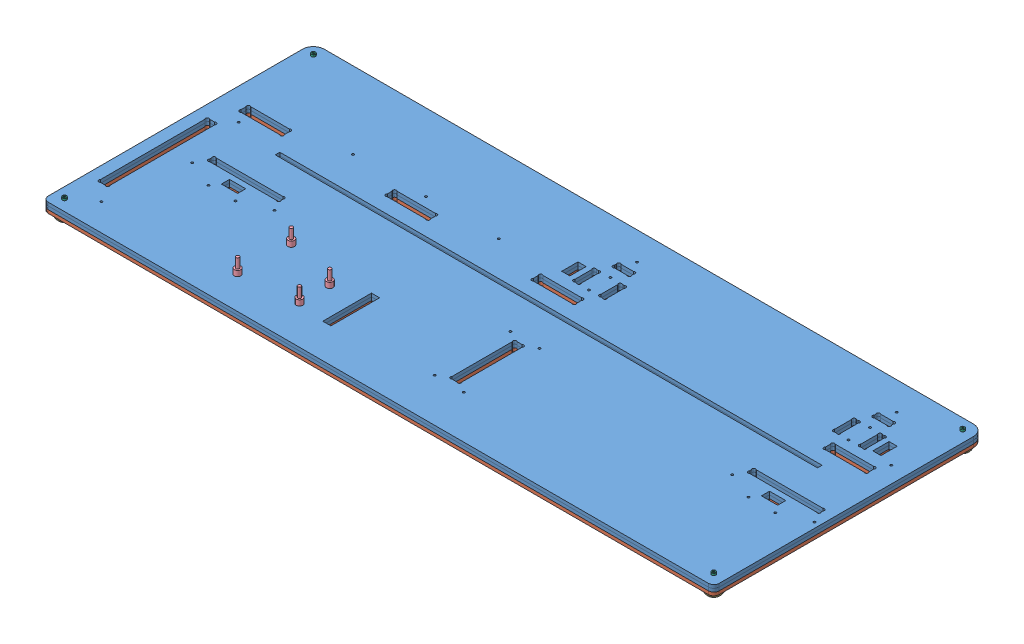
SolidWorks assembly socle-complet, configuration Défaut. Lengths in mm.
Overall size (621.62 30.74 251.62).
21 component instances, 6 part files, 49 mates.
Components (placement in the parent):
- socle-1-1: socle-1 [Défaut] at (-302.5453 40.1785 745) size (620 3 250)
- socle-1-2: socle-1 [Défaut] at (-302.5453 37.1785 745) size (620 3 250)
- socle-2-3: socle-2 [Défaut] at (-302.5453 34.1785 745) size (620 3 250)
- socle-patin-ecrou_m2-1: socle-patin-ecrou_m2 [Défaut] at (-292.5453 34.1785 735) x (0.367083 0 0.930188) z (-0.930188 0 0.367083) size (16 7.74 16)
- socle-patin-ecrou_m2-2: socle-patin-ecrou_m2 [Défaut] at (-292.5453 34.1785 505) x (-0.622025 0 0.782997) z (-0.782997 0 -0.622025) size (16 7.74 16)
- socle-patin-ecrou_m2-3: socle-patin-ecrou_m2 [Défaut] at (307.4547 34.1785 505) x (0.367083 0 0.930188) z (-0.930188 0 0.367083) size (16 7.74 16)
- socle-patin-ecrou_m2-4: socle-patin-ecrou_m2 [Défaut] at (307.4547 34.1785 735) x (0.367083 0 0.930188) z (-0.930188 0 0.367083) size (16 7.74 16)
- socle-carte_pied-1: socle-carte_pied [Défaut] at (-152.5453 38.1785 715) x (0 1 0) z (-0.920347 0 -0.391102) size (19 6 6)
- socle-carte_pied-2: socle-carte_pied [Défaut] at (-151.2753 38.1785 666.74) x (0 1 0) z (-0.842592 0 -0.538553) size (19 6 6)
- socle-carte_pied-3: socle-carte_pied [Défaut] at (-100.4753 38.1785 681.98) x (0 1 0) z (-0.819102 0 -0.573647) size (19 6 6)
- socle-carte_pied-4: socle-carte_pied [Défaut] at (-100.4753 38.1785 709.92) x (0 1 0) z (0.984574 0 0.174968) size (19 6 6)
- ecrou-h-1: ecrou-h [6007 HU M2] at (-292.5453 31.1785 735) size (4 1.6 4.62)
- vis-chc-1: vis-chc [Vis CHC M2x16] at (-292.5453 43.1785 735) x (0.999999 0 -0.001395) z (0.001395 0 0.999999) size (3.8 18 3.8)
- vis-chc-2: vis-chc [Vis CHC M2x16] at (307.4547 43.1785 735) x (0.999999 0 -0.001395) z (0.001395 0 0.999999) size (3.8 18 3.8)
- vis-chc-3: vis-chc [Vis CHC M2x16] at (-292.5453 43.1785 505) x (0.610012 0 -0.792392) z (0.792392 0 0.610012) size (3.8 18 3.8)
- vis-chc-4: vis-chc [Vis CHC M2x16] at (307.4547 43.1785 505) x (0.999999 0 -0.001395) z (0.001395 0 0.999999) size (3.8 18 3.8)
- ecrou-h-2: ecrou-h [6007 HU M2] at (307.4547 31.1785 735) size (4 1.6 4.62)
- ecrou-h-3: ecrou-h [6007 HU M2] at (307.4547 31.1785 505) size (4 1.6 4.62)
- ecrou-h-4: ecrou-h [6007 HU M2] at (-292.5453 31.1785 505) size (4 1.6 4.62)
- socle-patin-ecrou_m2-5: socle-patin-ecrou_m2 [Défaut] at (22.4547 34.1785 521) x (-0.256954 0 0.966424) z (-0.966424 0 -0.256954) size (16 7.74 16)
- socle-patin-ecrou_m2-6: socle-patin-ecrou_m2 [Défaut] at (19.4547 34.1785 705) x (0.367083 0 0.930188) z (-0.930188 0 0.367083) size (16 7.74 16)
Mates (geometry in assembly coordinates):
- Coïncidente1: coincident anti-aligned: plane of socle-1-1 through (-292.5453 40.1785 505) normal (0 -1 0); plane of socle-1-2 through (-292.5453 40.1785 505) normal (0 1 0)
- Coïncidente2: coincident aligned: plane of socle-1-1 through (-302.5453 43.1785 745) normal (0 0 1); plane of socle-1-2 through (-302.5453 40.1785 745) normal (0 0 1)
- Coïncidente3: coincident aligned: plane of socle-1-1 through (-302.5453 43.1785 505) normal (-1 0 0); plane of socle-1-2 through (-302.5453 40.1785 505) normal (-1 0 0)
- Coïncidente4: coincident anti-aligned: plane of socle-1-2 through (-292.5453 37.1785 505) normal (0 -1 0); plane of socle-3 through (-292.5453 37.1785 505) normal (0 1 0)
- Coïncidente5: coincident aligned: plane of socle-1-2 through (-302.5453 40.1785 745) normal (0 0 1); plane of socle-3 through (-302.5453 37.1785 745) normal (0 0 1)
- Coïncidente6: coincident aligned: plane of socle-1-2 through (-302.5453 40.1785 505) normal (-1 0 0); plane of socle-3 through (-302.5453 37.1785 505) normal (-1 0 0)
- Coaxiale1: concentric anti-aligned: cylinder of socle-3 through (-292.5453 37.1785 735) axis (0 -1 0) radius 1; cylinder of socle-patin-ecrou_m2-1 through (-292.5453 26.1785 735) axis (0 1 0) radius 1
- Coïncidente7: coincident anti-aligned: plane of socle-3 through (-292.5453 34.1785 505) normal (0 -1 0); plane of socle-patin-ecrou_m2-1 through (-295.482 34.1785 727.5585) normal (0 1 0)
- Coaxiale2: concentric anti-aligned: cylinder of socle-3 through (307.4547 37.1785 735) axis (0 -1 0) radius 1; cylinder of socle-patin-ecrou_m2-4 through (307.4547 26.1785 735) axis (0 1 0) radius 1
- Coaxiale3: concentric anti-aligned: cylinder of socle-3 through (307.4547 37.1785 505) axis (0 -1 0) radius 1; cylinder of socle-patin-ecrou_m2-3 through (307.4547 26.1785 505) axis (0 1 0) radius 1
- Coaxiale4: concentric anti-aligned: cylinder of socle-3 through (-292.5453 37.1785 505) axis (0 -1 0) radius 1; cylinder of socle-patin-ecrou_m2-2 through (-292.5453 26.1785 505) axis (0 1 0) radius 1
- Coïncidente8: coincident anti-aligned: plane of socle-3 through (-292.5453 34.1785 505) normal (0 -1 0); plane of socle-patin-ecrou_m2-2 through (-287.5691 34.1785 498.736) normal (0 1 0)
- Coïncidente9: coincident anti-aligned: plane of socle-3 through (-292.5453 34.1785 505) normal (0 -1 0); plane of socle-patin-ecrou_m2-3 through (304.518 34.1785 497.5585) normal (0 1 0)
- Coïncidente10: coincident anti-aligned: plane of socle-3 through (-292.5453 34.1785 505) normal (0 -1 0); plane of socle-patin-ecrou_m2-4 through (304.518 34.1785 727.5585) normal (0 1 0)
- Parallèle1: parallel anti-aligned: plane of socle-3 through (317.4547 37.1785 505) normal (1 0 0); plane of socle-patin-ecrou_m2-4 through (309.4725 26.2413 736.165) normal (-1 0 0)
- Parallèle2: parallel anti-aligned: plane of socle-3 through (317.4547 37.1785 505) normal (1 0 0); plane of socle-patin-ecrou_m2-3 through (309.4725 26.2413 506.165) normal (-1 0 0)
- Parallèle3: parallel anti-aligned: plane of socle-3 through (-302.5453 37.1785 505) normal (-1 0 0); plane of socle-patin-ecrou_m2-1 through (-294.5631 26.2413 733.835) normal (1 0 0)
- Parallèle4: parallel anti-aligned: plane of socle-3 through (-302.5453 37.1785 505) normal (-1 0 0); plane of socle-patin-ecrou_m2-2 through (-294.5631 26.2413 503.835) normal (1 0 0)
- Coaxiale5: concentric aligned: cylinder of socle-1-1 through (-152.5453 40.1785 715) axis (0 1 0) radius 1.59; cylinder of socle-carte_pied-1 through (-152.5453 57.1785 715) axis (0 1 0) radius 1.5
- Coaxiale6: concentric aligned: cylinder of socle-1-1 through (-100.4753 40.1785 709.92) axis (0 1 0) radius 1.59; cylinder of socle-carte_pied-4 through (-100.4753 57.1785 709.92) axis (0 1 0) radius 1.5
- Coaxiale7: concentric aligned: cylinder of socle-1-1 through (-100.4753 40.1785 681.98) axis (0 1 0) radius 1.59; cylinder of socle-carte_pied-3 through (-100.4753 57.1785 681.98) axis (0 1 0) radius 1.5
- Coaxiale8: concentric aligned: cylinder of socle-1-1 through (-151.2753 40.1785 666.74) axis (0 1 0) radius 1.59; cylinder of socle-carte_pied-2 through (-151.2753 57.1785 666.74) axis (0 1 0) radius 1.5
- Coïncidente11: coincident anti-aligned: plane of socle-1-1 through (-292.5453 43.1785 505) normal (0 1 0); plane of socle-carte_pied-1 through (-151.9586 43.1785 713.6195) normal (0 -1 0)
- Coïncidente12: coincident anti-aligned: plane of socle-1-1 through (-292.5453 43.1785 505) normal (0 1 0); plane of socle-carte_pied-2 through (-150.4675 43.1785 665.4761) normal (0 -1 0)
- Coïncidente13: coincident anti-aligned: plane of socle-1-1 through (-292.5453 43.1785 505) normal (0 1 0); plane of socle-carte_pied-3 through (-99.6148 43.1785 680.7513) normal (0 -1 0)
- Coïncidente14: coincident anti-aligned: plane of socle-1-1 through (-292.5453 43.1785 505) normal (0 1 0); plane of socle-carte_pied-4 through (-100.7378 43.1785 711.3969) normal (0 -1 0)
- Coaxiale9: concentric anti-aligned: cylinder of socle-1-1 through (-292.5453 43.1785 735) axis (0 -1 0) radius 1; cylinder of vis-chc-1 through (-292.5453 27.1785 735) axis (0 1 0) radius 1
- Coïncidente15: coincident anti-aligned: plane of socle-1-1 through (-292.5453 43.1785 505) normal (0 1 0); plane of vis-chc-1 through (-292.5453 43.1785 735) normal (0 -1 0)
- Coaxiale10: concentric aligned: cylinder of ecrou-h-1 through (-292.5453 29.5785 735) axis (0 1 0) radius 0.7835; cylinder of vis-chc-1 through (-292.5453 27.1785 735) axis (0 1 0) radius 1
- Parallèle5: parallel anti-aligned: plane of socle-patin-ecrou_m2-1 through (-292.5453 26.2413 732.67) normal (0.5 0 0.866025); plane of ecrou-h-1 through (-292.5453 29.5785 732.6906) normal (-0.5 0 -0.866025)
- Coïncidente18: coincident anti-aligned: plane of socle-patin-ecrou_m2-1 through (-292.5453 31.1785 735) normal (0 -1 0); plane of ecrou-h-1 through (-290.5453 31.1785 733.8453) normal (0 1 0)
- Coaxiale11: concentric anti-aligned: cylinder of socle-1-1 through (307.4547 43.1785 735) axis (0 -1 0) radius 1; cylinder of vis-chc-2 through (307.4547 27.1785 735) axis (0 1 0) radius 1
- Coïncidente19: coincident aligned: plane of socle-1-1 through (-292.5453 43.1785 505) normal (0 1 0); circle of vis-chc-2
- Coaxiale12: concentric anti-aligned: cylinder of socle-1-1 through (307.4547 43.1785 505) axis (0 -1 0) radius 1; cylinder of vis-chc-4 through (307.4547 27.1785 505) axis (0 1 0) radius 1
- Coïncidente20: coincident anti-aligned: plane of socle-1-1 through (-292.5453 43.1785 505) normal (0 1 0); plane of vis-chc-4 through (307.4547 43.1785 505) normal (0 -1 0)
- Coaxiale13: concentric anti-aligned: cylinder of socle-1-1 through (-292.5453 43.1785 505) axis (0 -1 0) radius 1; cylinder of vis-chc-3 through (-292.5453 27.1785 505) axis (0 1 0) radius 1
- Coïncidente21: coincident anti-aligned: plane of socle-1-1 through (-292.5453 43.1785 505) normal (0 1 0); plane of vis-chc-3 through (-292.5453 43.1785 505) normal (0 -1 0)
- Coïncidente22: coincident anti-aligned: plane of socle-patin-ecrou_m2-2 through (-292.5453 31.1785 505) normal (0 -1 0); plane of ecrou-h-4 through (-290.5453 31.1785 503.8453) normal (0 1 0)
- Parallèle10: parallel anti-aligned: plane of socle-patin-ecrou_m2-2 through (-294.5631 26.2413 506.165) normal (0.5 0 -0.866025); plane of ecrou-h-4 through (-294.5453 29.5785 506.1547) normal (-0.5 0 0.866025)
- Coaxiale20: concentric aligned: cylinder of vis-chc-3 through (-292.5453 27.1785 505) axis (0 1 0) radius 1; cylinder of ecrou-h-4 through (-292.5453 29.5785 505) axis (0 1 0) radius 0.7835
- Coïncidente28: coincident anti-aligned: plane of socle-patin-ecrou_m2-3 through (307.4547 31.1785 505) normal (0 -1 0); plane of ecrou-h-3 through (309.4547 31.1785 503.8453) normal (0 1 0)
- Parallèle11: parallel anti-aligned: plane of socle-patin-ecrou_m2-3 through (305.4369 26.2413 506.165) normal (0.5 0 -0.866025); plane of ecrou-h-3 through (305.4547 29.5785 506.1547) normal (-0.5 0 0.866025)
- Coaxiale21: concentric aligned: cylinder of vis-chc-4 through (307.4547 27.1785 505) axis (0 1 0) radius 1; cylinder of ecrou-h-3 through (307.4547 29.5785 505) axis (0 1 0) radius 0.7835
- Coïncidente30: coincident anti-aligned: plane of socle-patin-ecrou_m2-4 through (307.4547 31.1785 735) normal (0 -1 0); plane of ecrou-h-2 through (309.4547 31.1785 733.8453) normal (0 1 0)
- Parallèle13: parallel anti-aligned: plane of socle-patin-ecrou_m2-4 through (307.4547 26.2413 737.33) normal (-0.5 0 -0.866025); plane of ecrou-h-2 through (307.4547 29.5785 737.3094) normal (0.5 0 0.866025)
- Coaxiale23: concentric aligned: cylinder of vis-chc-2 through (307.4547 27.1785 735) axis (0 1 0) radius 1; cylinder of ecrou-h-2 through (307.4547 29.5785 735) axis (0 1 0) radius 0.7835
- Coaxiale24: concentric: cylinder of socle-2-3 through (22.4547 34.1785 521) axis (0 1 0) radius 1; cylinder of socle-patin-ecrou_m2-5 through (22.4547 -62.7345 521) axis (0 1 0) radius 1
- Coaxiale25: concentric aligned: cylinder of socle-2-3 through (19.4547 34.1785 705) axis (0 1 0) radius 1; cylinder of socle-patin-ecrou_m2-6 through (19.4547 26.1785 705) axis (0 1 0) radius 1
- Coïncidente31: coincident anti-aligned: plane of socle-2-3 through (-292.5453 34.1785 505) normal (0 -1 0); plane of socle-patin-ecrou_m2-5 through (24.5103 34.1785 513.2686) normal (0 1 0)
